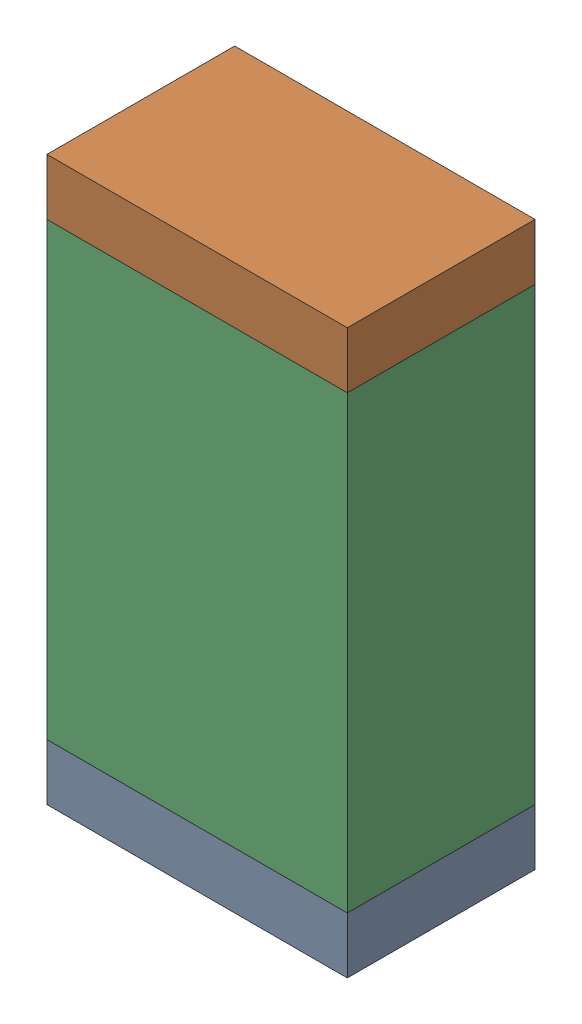
SolidWorks assembly R26, configuration Default. Lengths in mm.
Overall size (0.8 1.5 0.5).
6 component instances, 2 part files, 0 mates.
Components (placement in the parent):
- 810156592-1: 810156592 [Default] at (122.2 45.275 0) size (0.8 0.15 0.5)
  - Extruded_7-1: Extruded_7 [Default] at origin size (0.8 0.15 0.5)
- 810156592-2: 810156592 [Default] at (122.2 46.625 0) size (0.8 0.15 0.5)
  - Extruded_7-1: Extruded_7 [Default] at origin size (0.8 0.15 0.5)
- 810156976-1: 810156976 [Default] at (122.2 45.95 0) size (0.8 1.2 0.5)
  - Extruded_6-1: Extruded_6 [Default] at origin size (0.8 1.2 0.5)
